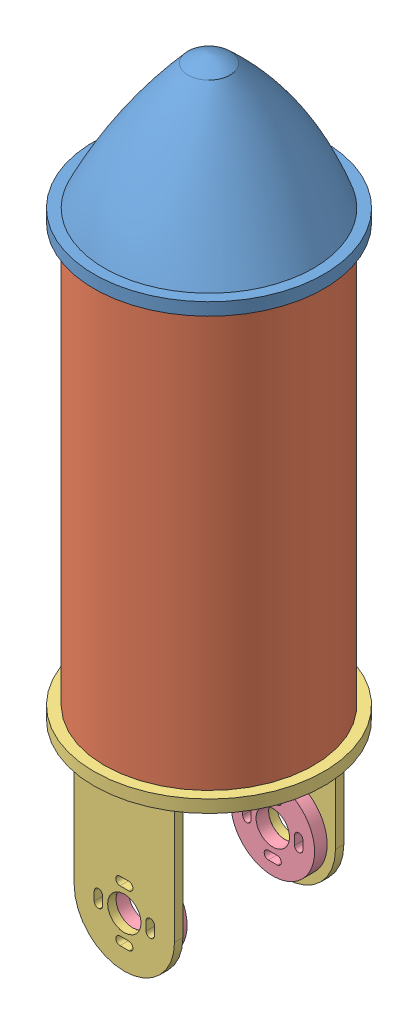
SolidWorks assembly base_link2, configuration 預設. Lengths in mm.
Overall size (69.26 179.98 69.26).
5 component instances, 4 part files, 17 mates.
Components (placement in the parent):
- bus_lib_head_1-2: bus_lib_head_1 [預設] at (0 50 -0.25) x (0.951482 0 0.307705) z (0.307705 0 -0.951482) size (55 54.98 55)
- bus_body-1: bus_body [預設] at (0 50 -0.25) x (0.989508 0 -0.144479) z (-0.144479 0 -0.989508) size (50 100 50)
- bus_lib_tail-1: bus_lib_tail [預設] at (0 -50 -0.25) size (55 65 55)
- bus_servo_cicrcle1-1: bus_servo_cicrcle1 [預設] at (0 -83 15) x (-1 0 0) z (0 0 1) size (20 20 3)
- bus_servo_cicrcle1-2: bus_servo_cicrcle1 [預設] at (0 -83 -18.5) x (-1 0 0) z (0 0 1) size (20 20 3)
Mates (geometry in assembly coordinates):
- 同軸心7: concentric: cylinder of bus_lib_head_1-2 through (12 35.5 -0.25) axis (0 1 0) radius 21.75; cylinder of bus_body-1 through (12 -50 -0.25) axis (0 1 0) radius 22
- 重合/共線/共點6: coincident: plane of bus_lib_head_1-2 through (12 50 -0.25) normal (0 -1 0); plane of bus_body-1 through (12 50 -0.25) normal (0 1 0)
- 同軸心8: concentric: cylinder of bus_body-1 through (12 -50 -0.25) axis (0 1 0) radius 22; cylinder of bus_lib_tail-1 through (12 -45 -0.25) axis (0 1 0) radius 21.75
- 重合/共線/共點7: coincident: plane of bus_body-1 through (12 -50 -0.25) normal (0 -1 0); plane of bus_lib_tail-1 through (12 -50 -0.25) normal (0 1 0)
- 平行相距1: distance = 18 mm: plane of assembly through (0 0 0) normal (0 0 1); plane of bus_lib_tail-1 through (0 -83 18) normal (0 0 -1)
- 平行相距2: distance = 50 mm: plane of bus_lib_tail-1 through (0 -50 -0.25) normal (0 1 0); plane of assembly through (0 0 0) normal (0 1 0)
- 平行4: parallel: plane of bus_lib_tail-1 through (0 -83 -18.5) normal (0 0 1); plane of assembly through (0 0 0) normal (0 0 1)
- 平行5: parallel: plane of bus_lib_tail-1 through (12 -50 -0.25) normal (0 1 0); plane of assembly through (0 0 0) normal (0 1 0)
- 重合/共線/共點14: coincident: plane of bus_lib_tail-1 through (12 -83 18) normal (0 0 -1); plane of bus_servo_cicrcle1-1 through (12 -83 18) normal (0 0 1)
- 同軸心9: concentric: cylinder of bus_lib_tail-1 through (12 -83 18) axis (0 0 1) radius 4; cylinder of bus_servo_cicrcle1-1 through (12 -83 19) axis (0 0 -1) radius 4
- 重合/共線/共點15: coincident: plane of bus_lib_tail-1 through (19.2 -81.95 18) normal (-1 0 0); plane of bus_servo_cicrcle1-1 through (19.2 -84.05 19) normal (-1 0 0)
- 重合/共線/共點16: coincident: plane of bus_lib_tail-1 through (6.8 -81.95 18) normal (-1 0 0); plane of bus_servo_cicrcle1-1 through (6.8 -84.05 19) normal (-1 0 0)
- 重合/共線/共點17: coincident: plane of bus_lib_tail-1 through (12 -83 -18.5) normal (0 0 1); plane of bus_servo_cicrcle1-2 through (12 -83 -18.5) normal (0 0 -1)
- 同軸心10: concentric: cylinder of bus_lib_tail-1 through (12 -83 -20.5) axis (0 0 1) radius 4; cylinder of bus_servo_cicrcle1-2 through (12 -83 -14.5) axis (0 0 -1) radius 4
- 重合/共線/共點18: coincident: plane of bus_lib_tail-1 through (10.95 -75.8 -20.5) normal (0 -1 0); plane of bus_servo_cicrcle1-2 through (13.05 -75.8 -14.5) normal (0 -1 0)
- 重合/共線/共點19: coincident: plane of bus_lib_tail-1 through (4.8 -81.95 -20.5) normal (1 0 0); plane of bus_servo_cicrcle1-2 through (4.8 -84.05 -14.5) normal (1 0 0)
- 平行相距5: distance = 12 mm: plane of assembly; plane of bus_lib_tail-1 through (12 -53 -20.5) normal (1 0 0)
